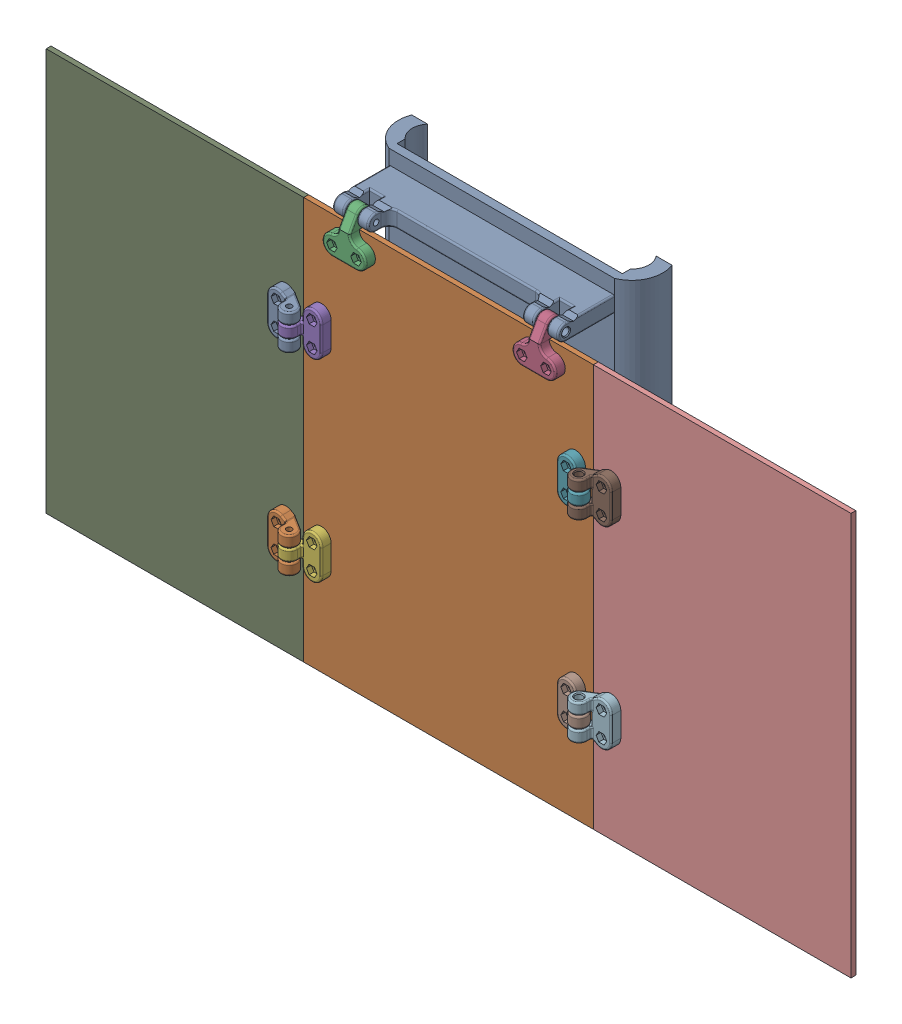
SolidWorks assembly Assemblage_Banderole, configuration Défaut. Lengths in mm.
Overall size (500 270 71.98).
14 component instances, 6 part files, 37 mates.
Components (placement in the parent):
- Maintien_Banderole-1: Maintien_Banderole [Défaut] at origin size (164.32 90 59.97)
- Panneau_Centre-1: Panneau_Centre [Défaut] at (0 -55 48.0386) size (180 250 3)
- Chraniere_Centre-1: Chraniere_Centre [Défaut] at (-59 59 55.5386) x (-1 0 0) z (0 0 -1) size (27 28 14.06)
- Chraniere_Centre-2: Chraniere_Centre [Défaut] at (59 59 55.5386) x (-1 0 0) z (0 0 -1) size (27 28 14.06)
- Chraniere_Lateral_1-1: Chraniere_Lateral_1 [Défaut] at (-79 5 52.5386) size (22 27 14.09)
- Chraniere_Lateral_1-2: Chraniere_Lateral_1 [Défaut] at (-79 -115 52.5386) size (22 27 14.09)
- Chraniere_Lateral_1-3: Chraniere_Lateral_1 [Défaut] at (79 5 52.5386) x (-1 0 0) z (0 0 1) size (22 27 14.09)
- Chraniere_Lateral_1-4: Chraniere_Lateral_1 [Défaut] at (79 -115 52.5386) x (-1 0 0) z (0 0 1) size (22 27 14.09)
- Panneau_Lateral-1: Panneau_Lateral [Défaut] at (-170 -55 48.0385) x (1 0 0) z (0 0 1) size (160 250 3)
- Panneau_Lateral-2: Panneau_Lateral [Défaut] at (169.9989 -55 48.0299) x (-1 0 0.000109) z (-0.000109 0 -1) size (160 250 3)
- Chraniere_Lateral_2-1: Chraniere_Lateral_2 [Défaut] at (100.9993 5 52.5374) x (1 0 -0.000109) z (0.000109 0 1) size (22 27 14)
- Chraniere_Lateral_2-2: Chraniere_Lateral_2 [Défaut] at (100.9993 -115 52.5374) x (1 0 -0.000109) z (0.000109 0 1) size (22 27 14)
- Chraniere_Lateral_2-3: Chraniere_Lateral_2 [Défaut] at (-101 5 52.5385) x (-1 0 0) z (0 0 1) size (22 27 14)
- Chraniere_Lateral_2-4: Chraniere_Lateral_2 [Défaut] at (-101 -115 52.5385) x (-1 0 0) z (0 0 1) size (22 27 14)
Mates (geometry in assembly coordinates):
- Coaxiale1: concentric anti-aligned: cylinder of Maintien_Banderole-1 through (86.4012 76 46.5386) axis (-1 0 0) radius 1.7; cylinder of Chraniere_Centre-1 through (-62.5 76 46.5386) axis (1 0 0) radius 1.7
- Coaxiale2: concentric anti-aligned: cylinder of Maintien_Banderole-1 through (86.4012 76 46.5386) axis (-1 0 0) radius 1.7; cylinder of Chraniere_Centre-2 through (55.5 76 46.5386) axis (1 0 0) radius 1.7
- Distance1: distance = 0.5 mm anti-aligned: plane of Chraniere_Centre-2 through (55.5 76 46.5386) normal (-1 0 0); plane of Maintien_Banderole-1 through (55 71 0) normal (1 0 0)
- Distance2: distance = 0.5 mm anti-aligned: plane of Chraniere_Centre-1 through (-55.5 76 46.5386) normal (1 0 0); plane of Maintien_Banderole-1 through (-55 71 0) normal (-1 0 0)
- Coaxiale3: concentric aligned: cylinder of Panneau_Centre-1 through (-55.8387 144.8846 46.8233) axis (0 0.016751 0.99986) radius 1.7; cylinder of Chraniere_Centre-1 through (-51.5 59.0526 49.8229) axis (0 0.016751 0.99986) radius 1.7
- Coaxiale4: concentric aligned: cylinder of Panneau_Centre-1 through (-70.8387 144.8846 46.8233) axis (0 0.016751 0.99986) radius 1.7; cylinder of Chraniere_Centre-1 through (-66.5 59.0526 49.8229) axis (0 0.016751 0.99986) radius 1.7
- Coïncidente3: coincident anti-aligned: plane of Panneau_Centre-1; plane of Chraniere_Centre-1
- Coïncidente5: coincident aligned: plane of Chraniere_Centre-1; plane of Chraniere_Centre-2
- Coïncidente6: coincident anti-aligned: plane of Panneau_Centre-1; plane of Chraniere_Lateral_1-1
- Coaxiale5: concentric anti-aligned: cylinder of Panneau_Centre-1 through (-83.3387 98.3911 47.6022) axis (0 0.016751 0.99986) radius 1.7; cylinder of Chraniere_Lateral_1-1 through (-79 12.6597 56.601) axis (0 -0.016751 -0.99986) radius 1.7
- Coaxiale6: concentric anti-aligned: cylinder of Panneau_Centre-1 through (-83.3387 83.3932 47.8535) axis (0 0.016751 0.99986) radius 1.7; cylinder of Chraniere_Lateral_1-1 through (-79 -2.3382 56.8522) axis (0 -0.016751 -0.99986) radius 1.7
- Coaxiale7: concentric anti-aligned: cylinder of Panneau_Centre-1 through (-83.3387 -21.5921 49.6124) axis (0 0.016751 0.99986) radius 1.7; cylinder of Chraniere_Lateral_1-2 through (-79 -107.3235 58.6111) axis (0 -0.016751 -0.99986) radius 1.7
- Coaxiale8: concentric anti-aligned: cylinder of Panneau_Centre-1 through (-83.3387 -36.59 49.8636) axis (0 0.016751 0.99986) radius 1.7; cylinder of Chraniere_Lateral_1-2 through (-79 -122.3214 58.8624) axis (0 -0.016751 -0.99986) radius 1.7
- Coïncidente7: coincident anti-aligned: plane of Panneau_Centre-1; plane of Chraniere_Lateral_1-2
- Coaxiale9: concentric anti-aligned: cylinder of Panneau_Centre-1 through (74.6613 -36.59 49.8636) axis (0 0.016751 0.99986) radius 1.7; cylinder of Chraniere_Lateral_1-4 through (79 -122.3214 58.8624) axis (0 -0.016751 -0.99986) radius 1.7
- Coaxiale10: concentric anti-aligned: cylinder of Panneau_Centre-1 through (74.6613 -21.5921 49.6124) axis (0 0.016751 0.99986) radius 1.7; cylinder of Chraniere_Lateral_1-4 through (79 -107.3235 58.6111) axis (0 -0.016751 -0.99986) radius 1.7
- Coaxiale11: concentric anti-aligned: cylinder of Panneau_Centre-1 through (74.6613 83.3932 47.8535) axis (0 0.016751 0.99986) radius 1.7; cylinder of Chraniere_Lateral_1-3 through (79 -2.3382 56.8522) axis (0 -0.016751 -0.99986) radius 1.7
- Coaxiale12: concentric anti-aligned: cylinder of Panneau_Centre-1 through (74.6613 98.3911 47.6022) axis (0 0.016751 0.99986) radius 1.7; cylinder of Chraniere_Lateral_1-3 through (79 12.6597 56.601) axis (0 -0.016751 -0.99986) radius 1.7
- Coïncidente8: coincident anti-aligned: plane of Panneau_Centre-1; plane of Chraniere_Lateral_1-3
- Coïncidente9: coincident anti-aligned: plane of Panneau_Centre-1; plane of Chraniere_Lateral_1-4
- Coaxiale13: concentric aligned: cylinder of Panneau_Lateral-2 through (100.999 -107.424 52.6108) axis (-0.000109 -0.016751 -0.99986) radius 1.7; cylinder of Chraniere_Lateral_2-2 through (100.9997 -107.3235 58.6099) axis (-0.000109 -0.016751 -0.99986) radius 1.7
- Coaxiale14: concentric aligned: cylinder of Panneau_Lateral-2 through (100.999 -122.4219 52.862) axis (-0.000109 -0.016751 -0.99986) radius 1.7; cylinder of Chraniere_Lateral_2-2 through (100.9997 -122.3214 58.8612) axis (-0.000109 -0.016751 -0.99986) radius 1.7
- Coaxiale15: concentric aligned: cylinder of Panneau_Lateral-2 through (100.999 12.5591 50.6006) axis (-0.000109 -0.016751 -0.99986) radius 1.7; cylinder of Chraniere_Lateral_2-1 through (100.9997 12.6596 56.5998) axis (-0.000109 -0.016751 -0.99986) radius 1.7
- Coaxiale16: concentric aligned: cylinder of Panneau_Lateral-2 through (100.999 -2.4388 50.8519) axis (-0.000109 -0.016751 -0.99986) radius 1.7; cylinder of Chraniere_Lateral_2-1 through (100.9997 -2.3382 56.8511) axis (-0.000109 -0.016751 -0.99986) radius 1.7
- Coïncidente10: coincident anti-aligned: plane of Panneau_Lateral-2; plane of Chraniere_Lateral_2-1
- Coïncidente11: coincident anti-aligned: plane of Panneau_Lateral-2; plane of Chraniere_Lateral_2-2
- Coïncidente12: coincident anti-aligned: plane of Panneau_Lateral-1; plane of Chraniere_Lateral_2-3
- Coïncidente13: coincident anti-aligned: plane of Panneau_Lateral-1; plane of Chraniere_Lateral_2-4
- Coaxiale17: concentric anti-aligned: cylinder of Panneau_Lateral-1 through (-101 -122.4721 49.8636) axis (0 0.016751 0.99986) radius 1.7; cylinder of Chraniere_Lateral_2-4 through (-101 -122.3214 58.8624) axis (0 -0.016751 -0.99986) radius 1.7
- Coaxiale18: concentric anti-aligned: cylinder of Panneau_Lateral-1 through (-101 -107.4743 49.6124) axis (0 0.016751 0.99986) radius 1.7; cylinder of Chraniere_Lateral_2-4 through (-101 -107.3235 58.6111) axis (0 -0.016751 -0.99986) radius 1.7
- Coaxiale19: concentric anti-aligned: cylinder of Panneau_Lateral-1 through (-101 12.5089 47.6022) axis (0 0.016751 0.99986) radius 1.7; cylinder of Chraniere_Lateral_2-3 through (-101 12.6597 56.601) axis (0 -0.016751 -0.99986) radius 1.7
- Coaxiale20: concentric anti-aligned: cylinder of Panneau_Lateral-1 through (-101 -2.489 47.8535) axis (0 0.016751 0.99986) radius 1.7; cylinder of Chraniere_Lateral_2-3 through (-101 -2.3382 56.8522) axis (0 -0.016751 -0.99986) radius 1.7
- Coaxiale21: concentric anti-aligned: cylinder of Chraniere_Lateral_1-1 through (-90 8.7105 59.6676) axis (0 -0.99986 0.016751) radius 1.7; cylinder of Chraniere_Lateral_2-3 through (-90 -5.7875 59.9105) axis (0 0.99986 -0.016751) radius 1.7
- Coaxiale22: concentric anti-aligned: cylinder of Chraniere_Lateral_1-3 through (90 1.7115 59.7848) axis (0 0.99986 -0.016751) radius 1.7; cylinder of Chraniere_Lateral_2-1 through (90 16.2094 59.5419) axis (0 -0.99986 0.016751) radius 1.7
- Distance3: distance = 0.5 mm anti-aligned: plane of Chraniere_Lateral_1-3 through (90 8.5 58.5386) normal (0 1 0); plane of Chraniere_Lateral_2-1 through (95.0005 9 63.538) normal (0 -1 0)
- Distance4: distance = 0.5 mm anti-aligned: plane of Chraniere_Lateral_1-1 through (-90 8.5 58.5386) normal (0 1 0); plane of Chraniere_Lateral_2-3 through (-95 9 63.5386) normal (0 -1 0)
- Parallèle1: parallel anti-aligned: plane of Maintien_Banderole-1 through (0 90 16.5386) normal (0 0 1); plane of Panneau_Centre-1 through (0 -55 46.5386) normal (0 0 -1)
